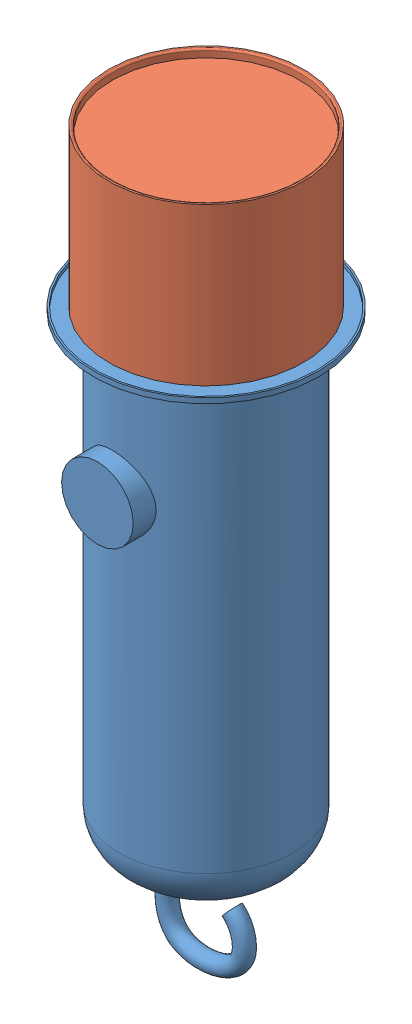
SolidWorks assembly Werkende lamp project lamp, configuration Default. Lengths in mm.
Overall size (80.05 214.2 80.05).
2 component instances, 2 part files, 1 mates.
Components (placement in the parent):
- Lamp project solidworks-1: Lamp project solidworks [Default] at (80.5555 43.2036 134.9934) size (66 168.35 66)
- Lamp project solidworks 2-2: Lamp project solidworks 2 [Default] at (55.5555 215.0507 134.9934) x (0.78542 0 0.618963) z (0.618963 0 -0.78542) size (57 171 57)
Mates (geometry in assembly coordinates):
- Concentric6: concentric anti-aligned: cylinder of Lamp project solidworks-1 through (55.5555 168.2036 134.9934) axis (0 1 0) radius 25; circle of Lamp project solidworks 2-2
